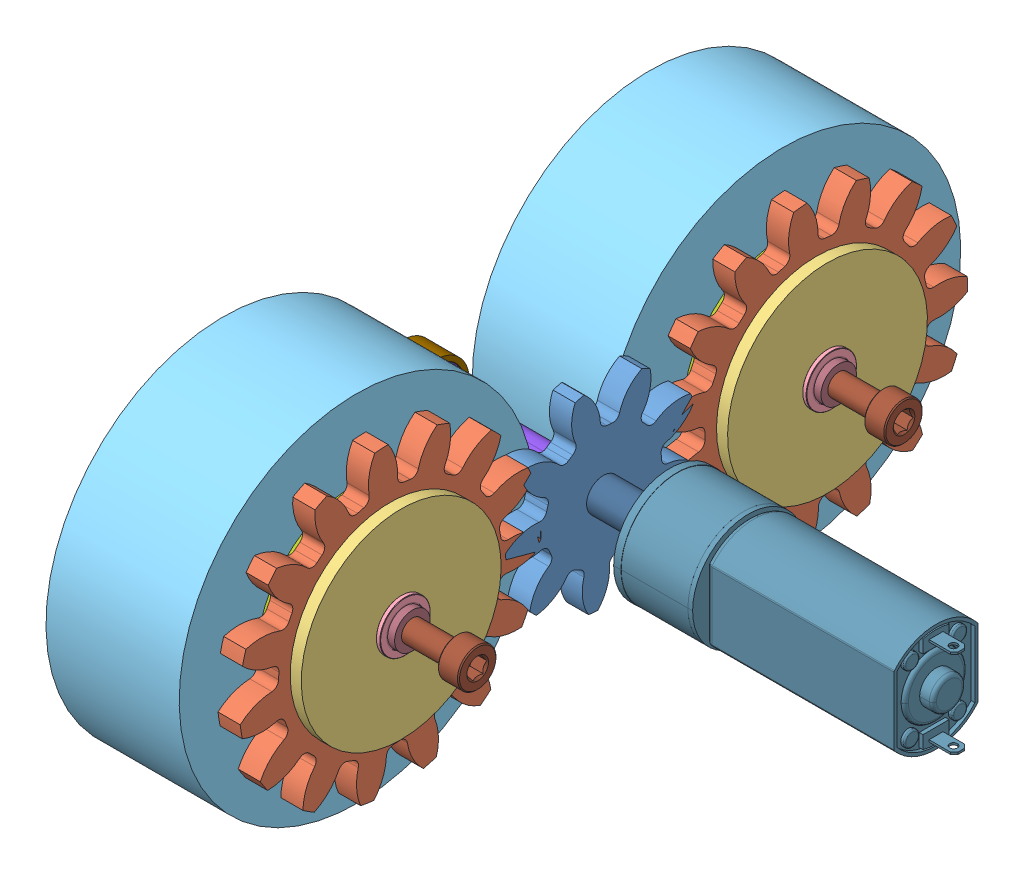
SolidWorks assembly Drive Assembly, configuration Default. Lengths in mm.
Overall size (81.96 71.79 129.94).
29 component instances, 14 part files, 52 mates.
Components (placement in the parent):
- 9T 10DP Gear-1: 9T 10DP Gear [Default] at (-23.9525 0 0) x (0 -0.704948 0.709259) z (1 0 0) size (27.36 27.71 3.17)
- 15T 10DP Gear-1: 15T 10DP Gear [Default] at (-23.9525 0 30.48) x (0 0.926702 0.375797) z (1 0 0) size (43.1 42.93 3.17)
- Gear Hub-1: Gear Hub [Default] at (-20.7775 0 30.48) x (0 -0.926702 -0.375797) z (-1 0 0) size (28.57 28.57 25.4)
- 3 mm Flanged Bearing 57155K538-1: 3 mm Flanged Bearing 57155K538 [57155K538] at (-19.84 0 30.48) x (0 0.990393 0.138284) z (-1 0 0) size (7.2 7.2 2.5)
- Wheel-1: Wheel [Default] at (-35.065 0 30.48) x (0 0.926702 0.375797) z (1 0 0) size (50.8 50.8 19.05)
- Wheel Retainer-1: Wheel Retainer [Default] at (-44.59 0 30.48) x (0 -0.940195 -0.340637) z (-1 0 0) size (12.7 12.7 10.53)
- 3 mm Flanged Bearing 57155K538-2: 3 mm Flanged Bearing 57155K538 [57155K538] at (-44.94 0 30.48) x (0 0.017248 0.999851) z (1 0 0) size (7.2 7.2 2.5)
- Gear Spacer-1: Gear Spacer [Default] at (-24.7463 0 30.48) x (0 0.926702 0.375797) z (1 0 0) size (28.57 28.57 1.59)
- Wheel-2: Wheel [Default] at (-35.065 0 -30.48) x (0 0.680668 -0.732592) z (1 0 0) size (50.8 50.8 19.05)
- 3 mm Flanged Bearing 57155K538-3: 3 mm Flanged Bearing 57155K538 [57155K538] at (-19.84 0 -30.48) x (0 0.996899 0.078694) z (-1 0 0) size (7.2 7.2 2.5)
- Wheel Retainer-2: Wheel Retainer [Default] at (-44.59 0 -30.48) x (0 -0.940195 -0.340637) z (-1 0 0) size (12.7 12.7 10.53)
- Gear Spacer-2: Gear Spacer [Default] at (-24.7463 0 -30.48) x (0 0.680668 -0.732592) z (1 0 0) size (28.57 28.57 1.59)
- 15T 10DP Gear-2: 15T 10DP Gear [Default] at (-23.9525 0 -30.48) x (0 0.680668 -0.732592) z (1 0 0) size (43.1 42.93 3.17)
- 3 mm Flanged Bearing 57155K538-4: 3 mm Flanged Bearing 57155K538 [57155K538] at (-44.94 0 -30.48) x (0 0.017248 0.999851) z (1 0 0) size (7.2 7.2 2.5)
- Gear Hub-2: Gear Hub [Default] at (-20.7775 0 -30.48) x (0 -0.680668 0.732592) z (-1 0 0) size (28.57 28.57 25.4)
- Lite_Hub-1: Lite_Hub [Default] at (-34.0659 -0.8768 1.7329) x (1 0 0) z (0 0.919814 0.392355) size (25.61 15 9.51)
  - Lite_Hub.IGS-1: Lite_Hub.IGS [Default] at origin size (25.61 15 9.51)
    - Lite hubs.IGS-1: Lite hubs.IGS [Default] at (-15.2866 1.938 0.1266) size (25.41 15 8.06)
    - Hub Sleeve R2.IGS-1: Hub Sleeve R2.IGS [Default] at (-10.6565 1.938 0.1266) x (0 0 1) z (-1 0 0) size (9.51 9.51 4.84)
- Drive Gear Spacer-1: Drive Gear Spacer [Default] at (-16.0138 0 0) x (0 -0.973557 0.228446) z (1 0 0) size (4.76 4.76 9.53)
- M3 40 mm Long Socket Head 91290A136-1: M3 40 mm Long Socket Head 91290A136 [91290A136] at (-29.75 0 30.48) x (0 -0.388378 -0.9215) z (1 0 0) size (5.5 5.5 43.33)
- M3 Locknut 90576A102-1: M3 Locknut 90576A102 [90576A102] at (-49.19 0 30.48) x (0 0.75361 0.657321) z (-1 0 0) size (5.5 6.35 4.19)
- Bearing Spacer-1: Bearing Spacer [Default] at (-46.69 0 30.48) x (0 -0.119145 -0.992877) z (1 0 0) size (5.08 5.08 1)
- Bearing Spacer-2: Bearing Spacer [Default] at (-18.09 0 30.48) x (0 0 1) z (-1 0 0) size (5.08 5.08 1)
- M3 Locknut 90576A102-2: M3 Locknut 90576A102 [90576A102] at (-49.19 0 -30.48) x (0 -0.75361 0.657321) z (-1 0 0) size (5.5 6.35 4.19)
- Bearing Spacer-3: Bearing Spacer [Default] at (-46.69 0 -30.48) x (0 -0.119145 0.992877) z (-1 0 0) size (5.08 5.08 1)
- M3 40 mm Long Socket Head 91290A136-2: M3 40 mm Long Socket Head 91290A136 [91290A136] at (-29.75 0 -30.48) x (0 0.388378 -0.9215) z (1 0 0) size (5.5 5.5 43.33)
- Bearing Spacer-4: Bearing Spacer [Default] at (-18.09 0 -30.48) x (0 0 -1) z (1 0 0) size (5.08 5.08 1)
- FingerTech_Silver_Spark_223350-2: FingerTech_Silver_Spark_223350 [Default] at origin size (79.67 16.08 16.08)
Mates (geometry in assembly coordinates):
- Coincident2: coincident: line of 9T 10DP Gear-1 through (0 100 26.0475) axis (0 0 -1)
- Coincident3: coincident: line of 9T 10DP Gear-1 through (0 100 26.0475) axis (0 0 -1)
- Coincident4: coincident: line of 15T 10DP Gear-1 through (26.0475 0 30.48) axis (-1 0 0)
- Distance1: distance = 30.48 mm: line of 15T 10DP Gear-1 through (26.0475 0 30.48) axis (-1 0 0)
- Coincident6: coincident aligned: plane of 9T 10DP Gear-1 through (-23.9525 0 0) normal (1 0 0); plane of 15T 10DP Gear-1 through (-23.9525 0 30.48) normal (1 0 0)
- Coincident7: coincident aligned: plane of 15T 10DP Gear-1 through (-23.9525 0 30.48) normal (0 -0.375797 0.926702); plane of Gear Hub-1 through (-20.7775 0 30.48) normal (0 -0.375797 0.926702)
- Coincident8: coincident anti-aligned: plane of 15T 10DP Gear-1 through (-23.9525 0 30.48) normal (0 0.926702 0.375797); plane of Gear Hub-1 through (-20.7775 0 30.48) normal (0 -0.926702 -0.375797)
- Coincident9: coincident anti-aligned: plane of 15T 10DP Gear-1 through (-20.7775 0 30.48) normal (1 0 0); plane of Gear Hub-1 through (-20.7775 0 30.48) normal (-1 0 0)
- Concentric3: concentric anti-aligned: cylinder of Gear Hub-1 through (-25.54 0 30.48) axis (1 0 0) radius 3; cylinder of 3 mm Flanged Bearing 57155K538-1 through (-19.84 0 30.48) axis (-1 0 0) radius 3
- Coincident10: coincident anti-aligned: plane of Gear Hub-1 through (-19.19 0 30.48) normal (1 0 0); plane of 3 mm Flanged Bearing 57155K538-1 through (-19.19 0.4978 26.9146) normal (-1 0 0)
- Coincident11: coincident anti-aligned: plane of Gear Hub-1 through (-20.7775 0 30.48) normal (0 -0.926702 -0.375797); plane of Wheel-1 through (-35.065 0 30.48) normal (0 0.926702 0.375797)
- Coincident12: coincident aligned: plane of Gear Hub-1 through (-20.7775 0 30.48) normal (0 -0.375797 0.926702); plane of Wheel-1 through (-35.065 0 30.48) normal (0 -0.375797 0.926702)
- Coincident13: coincident anti-aligned: plane of Gear Hub-1 through (-25.54 -0.6478 41.5736) normal (-1 0 0); plane of Wheel-1 through (-25.54 0 30.48) normal (1 0 0)
- Concentric4: concentric aligned: cylinder of Gear Hub-1 through (-25.54 0 30.48) axis (1 0 0) radius 3; cylinder of Wheel Retainer-1 through (-45.59 0 30.48) axis (1 0 0) radius 3
- Concentric5: concentric aligned: cylinder of Wheel Retainer-1 through (-45.59 0 30.48) axis (1 0 0) radius 3; cylinder of 3 mm Flanged Bearing 57155K538-2 through (-44.94 0 30.48) axis (1 0 0) radius 3
- Coincident16: coincident anti-aligned: plane of Gear Hub-1 through (-44.59 0 30.48) normal (-1 0 0); plane of Wheel Retainer-1 through (-44.59 0 30.48) normal (1 0 0)
- Coincident17: coincident anti-aligned: plane of Wheel Retainer-1 through (-45.59 0 30.48) normal (-1 0 0); plane of 3 mm Flanged Bearing 57155K538-2 through (-45.59 -3.5995 30.5421) normal (1 0 0)
- Coincident18: coincident anti-aligned: plane of Gear Hub-1 through (-20.7775 0 30.48) normal (0 -0.926702 -0.375797); plane of Gear Spacer-1 through (-24.7463 0 30.48) normal (0 0.926702 0.375797)
- Coincident19: coincident aligned: plane of Gear Hub-1 through (-20.7775 0 30.48) normal (0 -0.375797 0.926702); plane of Gear Spacer-1 through (-24.7463 0 30.48) normal (0 -0.375797 0.926702)
- Coincident20: coincident anti-aligned: plane of 15T 10DP Gear-1 through (-23.9525 0 30.48) normal (-1 0 0); plane of Gear Spacer-1 through (-23.9525 0 30.48) normal (1 0 0)
- Concentric6: concentric anti-aligned: cylinder of 3 mm Flanged Bearing 57155K538-3 through (-19.84 0 -30.48) axis (-1 0 0) radius 3; cylinder of Gear Hub-2 through (-25.54 0 -30.48) axis (1 0 0) radius 3
- Concentric7: concentric aligned: cylinder of Wheel Retainer-2 through (-45.59 0 -30.48) axis (1 0 0) radius 3; cylinder of Gear Hub-2 through (-25.54 0 -30.48) axis (1 0 0) radius 3
- Concentric8: concentric aligned: cylinder of Wheel Retainer-2 through (-45.59 0 -30.48) axis (1 0 0) radius 3; cylinder of 3 mm Flanged Bearing 57155K538-4 through (-44.94 0 -30.48) axis (1 0 0) radius 3
- Coincident21: coincident anti-aligned: plane of Gear Spacer-2 through (-23.9525 0 -30.48) normal (1 0 0); plane of 15T 10DP Gear-2 through (-23.9525 0 -30.48) normal (-1 0 0)
- Coincident22: coincident anti-aligned: plane of Gear Spacer-2 through (-24.7463 0 -30.48) normal (0 0.680668 -0.732592); plane of Gear Hub-2 through (-20.7775 0 -30.48) normal (0 -0.680668 0.732592)
- Coincident23: coincident anti-aligned: plane of 3 mm Flanged Bearing 57155K538-3 through (-19.19 0.2833 -34.0688) normal (-1 0 0); plane of Gear Hub-2 through (-19.19 0 -30.48) normal (1 0 0)
- Coincident24: coincident aligned: plane of Gear Spacer-2 through (-24.7463 0 -30.48) normal (0 0.732592 0.680668); plane of Gear Hub-2 through (-20.7775 0 -30.48) normal (0 0.732592 0.680668)
- Coincident25: coincident aligned: plane of 15T 10DP Gear-2 through (-23.9525 0 -30.48) normal (0 0.732592 0.680668); plane of Gear Hub-2 through (-20.7775 0 -30.48) normal (0 0.732592 0.680668)
- Coincident26: coincident anti-aligned: plane of 15T 10DP Gear-2 through (-23.9525 0 -30.48) normal (0 0.680668 -0.732592); plane of Gear Hub-2 through (-20.7775 0 -30.48) normal (0 -0.680668 0.732592)
- Coincident27: coincident anti-aligned: plane of 15T 10DP Gear-2 through (-20.7775 0 -30.48) normal (1 0 0); plane of Gear Hub-2 through (-20.7775 0 -30.48) normal (-1 0 0)
- Coincident28: coincident anti-aligned: plane of Wheel-2 through (-35.065 0 -30.48) normal (0 0.680668 -0.732592); plane of Gear Hub-2 through (-20.7775 0 -30.48) normal (0 -0.680668 0.732592)
- Coincident29: coincident aligned: plane of Wheel-2 through (-35.065 0 -30.48) normal (0 0.732592 0.680668); plane of Gear Hub-2 through (-20.7775 0 -30.48) normal (0 0.732592 0.680668)
- Coincident30: coincident anti-aligned: plane of Wheel-2 through (-25.54 0 -30.48) normal (1 0 0); plane of Gear Hub-2 through (-25.54 10.1388 -25.931) normal (-1 0 0)
- Coincident31: coincident anti-aligned: plane of Wheel Retainer-2 through (-44.59 0 -30.48) normal (1 0 0); plane of Gear Hub-2 through (-44.59 0 -30.48) normal (-1 0 0)
- Coincident32: coincident anti-aligned: plane of Wheel Retainer-2 through (-45.59 0 -30.48) normal (-1 0 0); plane of 3 mm Flanged Bearing 57155K538-4 through (-45.59 -3.5995 -30.4179) normal (1 0 0)
- Coincident33: coincident: line of 15T 10DP Gear-2 through (26.0475 0 -30.48) axis (-1 0 0)
- Distance2: distance = 30.48 mm: line of assembly; plane of assembly; line of 15T 10DP Gear-2 through (26.0475 0 -30.48) axis (-1 0 0)
- Coincident35: coincident aligned: plane of 9T 10DP Gear-1 through (-23.9525 0 0) normal (1 0 0); plane of 15T 10DP Gear-2 through (-23.9525 0 -30.48) normal (1 0 0)
- Coincident39: coincident: line of Lite_Hub-1 through (0 25.402 -23.9515) axis (0 0 -1)
- Coincident40: coincident: line of Lite_Hub-1 through (0 25.402 -23.9515) axis (0 0 -1)
- Tangent7: tangent anti-aligned: plane of 9T 10DP Gear-1 through (-23.9525 0 0) normal (-1 0 0); face of Lite_Hub-1/Lite_Hub.IGS-1/Lite hubs.IGS-1
- Concentric10: concentric aligned: cylinder of 3 mm Flanged Bearing 57155K538-1 through (-19.84 0 30.48) axis (-1 0 0) radius 1.5; cylinder of M3 40 mm Long Socket Head 91290A136-1 through (-51.25 0 30.48) axis (-1 0 0) radius 1.5541
- Concentric12: concentric anti-aligned: cylinder of M3 40 mm Long Socket Head 91290A136-1 through (-51.25 0 30.48) axis (-1 0 0) radius 1.5541; cylinder of M3 Locknut 90576A102-1 through (-47.19 0 30.48) axis (1 0 0) radius 1.1752
- Concentric13: concentric anti-aligned: cylinder of 3 mm Flanged Bearing 57155K538-2 through (-44.94 0 30.48) axis (1 0 0) radius 1.825; cylinder of Bearing Spacer-1 through (-46.19 0 30.48) axis (-1 0 0) radius 1.5
- Coincident45: coincident anti-aligned: plane of 3 mm Flanged Bearing 57155K538-2 through (-46.19 -1.9872 30.5143) normal (-1 0 0); plane of Bearing Spacer-1 through (-46.19 0 30.48) normal (1 0 0)
- Coincident46: coincident anti-aligned: plane of M3 Locknut 90576A102-1 through (-47.19 0 30.48) normal (1 0 0); plane of Bearing Spacer-1 through (-47.19 0 30.48) normal (-1 0 0)
- Coincident47: coincident anti-aligned: plane of 3 mm Flanged Bearing 57155K538-1 through (-18.59 0.2748 28.5116) normal (1 0 0); plane of Bearing Spacer-2 through (-18.59 0 30.48) normal (-1 0 0)
- Concentric15: concentric anti-aligned: cylinder of M3 40 mm Long Socket Head 91290A136-1 through (-51.25 0 30.48) axis (-1 0 0) radius 1.5541; cylinder of Bearing Spacer-2 through (-18.59 0 30.48) axis (1 0 0) radius 1.5
- Coincident48: coincident aligned: plane of M3 40 mm Long Socket Head 91290A136-1 through (-11.25 2.3959 29.4702) normal (-1 0 0); plane of FingerTech_Silver_Spark_223350-2 through (-11.25 0 0) normal (-1 0 0)
- Concentric16: concentric anti-aligned: cylinder of Drive Gear Spacer-1 through (-11.25 0 0) axis (-1 0 0) radius 1.5; cylinder of FingerTech_Silver_Spark_223350-2 through (-49.26 0 0) axis (1 0 0) radius 1.49
- Coincident49: coincident anti-aligned: plane of Drive Gear Spacer-1 through (-11.25 0 0) normal (1 0 0); plane of FingerTech_Silver_Spark_223350-2 through (-11.25 0 0) normal (-1 0 0)
- Coincident50: coincident anti-aligned: plane of 9T 10DP Gear-1 through (-20.7775 0 0) normal (1 0 0); plane of Drive Gear Spacer-1 through (-20.7775 0 0) normal (-1 0 0)
